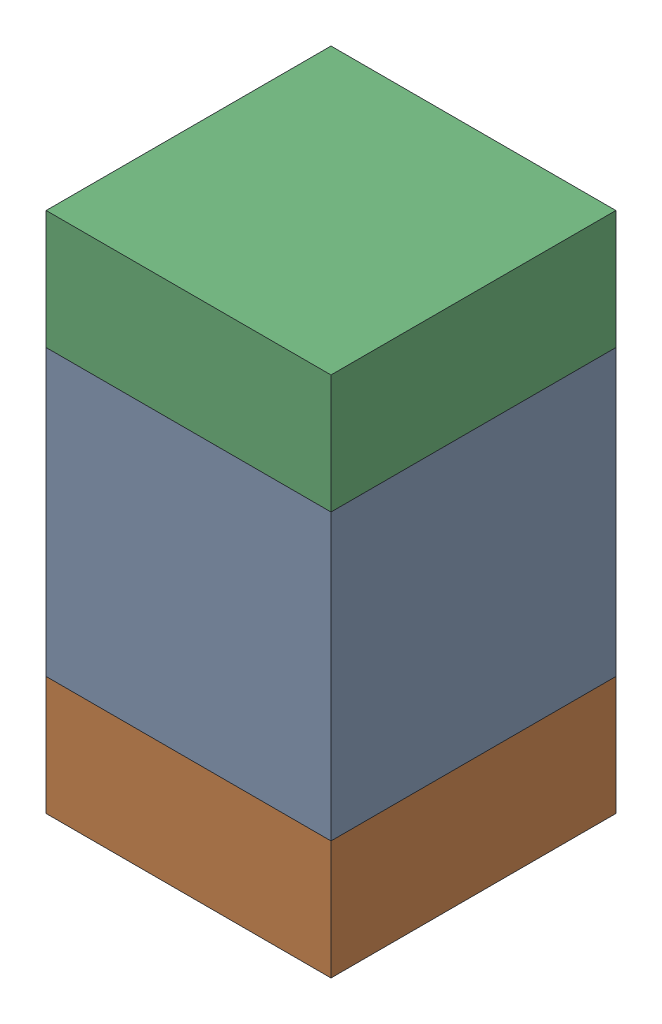
SolidWorks assembly C305_1PCB, configuration Default. Lengths in mm.
Overall size (0.6 1.1 0.6).
6 component instances, 2 part files, 0 mates.
Components (placement in the parent):
- 761606048-1: 761606048 [Default] at (143.225 115.6 0) size (0.6 0.6 0.6)
  - Extruded_9-1: Extruded_9 [Default] at origin size (0.6 0.6 0.6)
- 854785296-1: 854785296 [Default] at (143.225 115.175 0) size (0.6 0.25 0.6)
  - Extruded_10-1: Extruded_10 [Default] at origin size (0.6 0.25 0.6)
- 854785296-2: 854785296 [Default] at (143.225 116.025 0) size (0.6 0.25 0.6)
  - Extruded_10-1: Extruded_10 [Default] at origin size (0.6 0.25 0.6)
